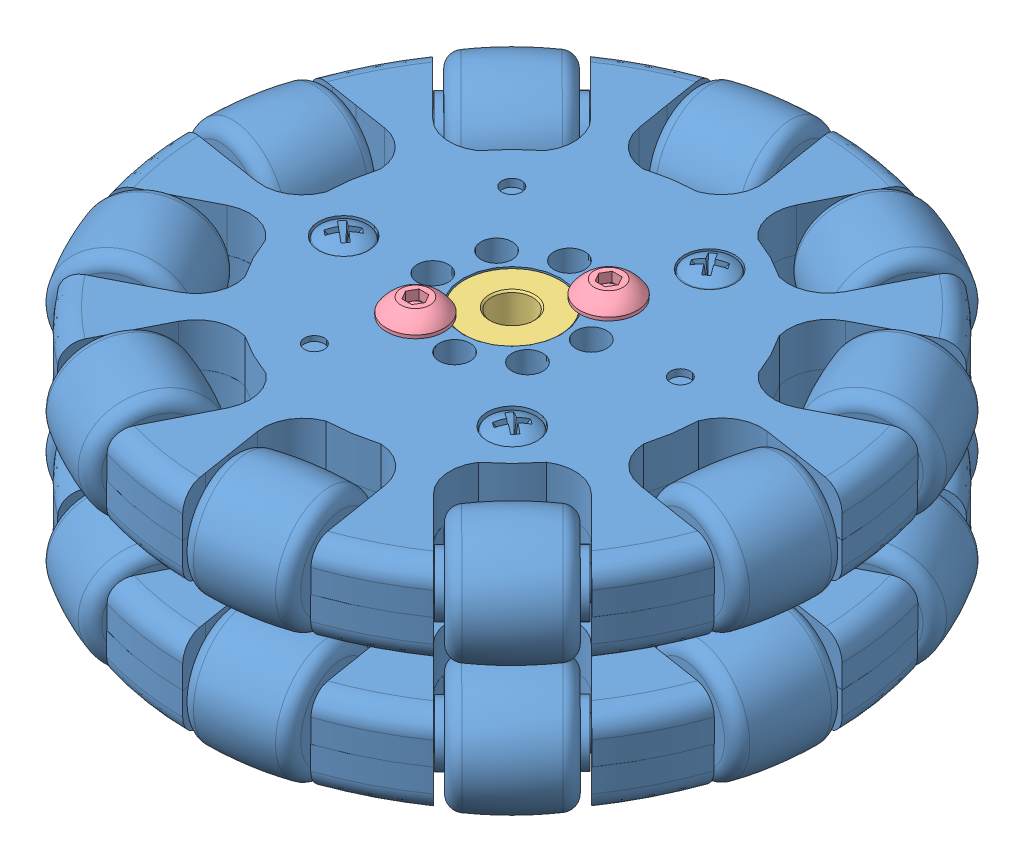
SolidWorks assembly Omni dual wheel spinner, configuration Default. Lengths in mm.
Overall size (77.7 28.71 77.72).
9 component instances, 4 part files, 24 mates.
Components (placement in the parent):
- 3-inch omni single wheel part-1: 3-inch omni single wheel part [Default] at (8.7963 -3.939 -0.2393) size (77.7 13.48 77.72)
- Omni wheel joining hub-1: Omni wheel joining hub [Default] at (1.7244 6.4355 -0.2049) x (0.809625 0 0.586947) z (0 -1 0) size (22 22 5)
- 3-inch omni single wheel part-2: 3-inch omni single wheel part [Default] at (8.7963 11.061 -0.2393) size (77.7 13.48 77.72)
- Axle bronze bushing-1: Axle bronze bushing [Default] at (1.7244 -5.9645 -0.2049) x (0.809625 0 0.586947) z (0 -1 0) size (11 11 12.4)
- Axle bronze bushing-2: Axle bronze bushing [Default] at (1.7244 18.8355 -0.2049) x (-0.809625 0 -0.586947) z (0 1 0) size (11 11 12.4)
- Socket Button Head Cap Screw_AI-2: Socket Button Head Cap Screw_AI [SBHCSCREW 0.138-32x0.5-HX-N] at (-2.9695 20.7897 6.2733) x (0 -1 0) z (0 0 1) size (14.55 6.65 6.65)
- Socket Button Head Cap Screw_AI-3: Socket Button Head Cap Screw_AI [SBHCSCREW 0.138-32x0.5-HX-N] at (6.4183 20.7897 -6.6831) x (0 -1 0) z (0 0 1) size (14.55 6.65 6.65)
- Socket Button Head Cap Screw_AI-4: Socket Button Head Cap Screw_AI [SBHCSCREW 0.138-32x0.5-HX-N] at (-2.9712 -7.9187 6.2721) x (0 1 0) z (0 0 1) size (14.55 6.65 6.65)
- Socket Button Head Cap Screw_AI-5: Socket Button Head Cap Screw_AI [SBHCSCREW 0.138-32x0.5-HX-N] at (6.42 -7.9187 -6.6819) x (0 1 0) z (0 0 1) size (14.55 6.65 6.65)
Mates (geometry in assembly coordinates):
- Concentric1: concentric aligned: circle of 3-inch omni single wheel part-1; cylinder of Axle bronze bushing-1 through (1.7244 6.4355 -0.2049) axis (0 -1 0) radius 3.925
- Concentric3: concentric anti-aligned: cylinder of 3-inch omni single wheel part-1 through (1.7244 -1.0645 -0.2049) axis (0 1 0) radius 4; cylinder of Omni wheel joining hub-1 through (1.7244 8.9355 -0.2049) axis (0 -1 0) radius 4
- Coincident2: coincident anti-aligned: plane of 3-inch omni single wheel part-1 through (-11.9708 3.9355 22.6509) normal (0 1 0); plane of Omni wheel joining hub-1 through (1.7244 3.9355 -0.2049) normal (0 -1 0)
- Coincident11: coincident: point of 3-inch omni single wheel part-1; plane of Omni wheel joining hub-1
- Concentric4: concentric anti-aligned: cylinder of Omni wheel joining hub-1 through (1.7244 8.9355 -0.2049) axis (0 -1 0) radius 4; cylinder of 3-inch omni single wheel part-2 through (1.7244 13.9355 -0.2049) axis (0 1 0) radius 4
- Coincident5: coincident anti-aligned: plane of Omni wheel joining hub-1 through (1.7244 8.9355 -0.2049) normal (0 1 0); plane of 3-inch omni single wheel part-2 through (21.8529 8.9355 17.2533) normal (0 -1 0)
- Coincident12: coincident aligned: plane of 3-inch omni single wheel part-1 through (8.7963 -3.939 -0.2393) normal (0 0 1); plane of 3-inch omni single wheel part-2 through (8.7963 11.061 -0.2393) normal (0 0 1)
- Concentric5: concentric anti-aligned: cylinder of Axle bronze bushing-2 through (1.7244 6.4355 -0.2049) axis (0 1 0) radius 3.925; cylinder of 3-inch omni single wheel part-2 through (1.7244 13.9355 -0.2049) axis (0 -1 0) radius 4
- Concentric7: concentric aligned: cylinder of 3-inch omni single wheel part-2 through (-2.9695 13.9355 6.2733) axis (0 1 0) radius 1.8; cylinder of Socket Button Head Cap Screw_AI-2 through (-2.9695 20.7897 6.2733) axis (0 1 0) radius 3.3274
- Coincident6: coincident anti-aligned: plane of 3-inch omni single wheel part-2 through (-11.9708 18.9355 22.6509) normal (0 1 0); plane of Socket Button Head Cap Screw_AI-2 through (-1.2169 18.9355 6.2733) normal (0 -1 0)
- Concentric8: concentric aligned: cylinder of 3-inch omni single wheel part-2 through (6.4183 13.9355 -6.6831) axis (0 1 0) radius 1.8; cylinder of Socket Button Head Cap Screw_AI-3 through (6.4183 20.7897 -6.6831) axis (0 1 0) radius 3.3274
- Coincident7: coincident anti-aligned: plane of 3-inch omni single wheel part-2 through (-11.9708 18.9355 22.6509) normal (0 1 0); plane of Socket Button Head Cap Screw_AI-3 through (8.1709 18.9355 -6.6831) normal (0 -1 0)
- Concentric9: concentric aligned: cylinder of 3-inch omni single wheel part-1 through (-2.9712 -1.0645 6.2721) axis (0 -1 0) radius 1.8; cylinder of Socket Button Head Cap Screw_AI-4 through (-2.9712 -7.9187 6.2721) axis (0 -1 0) radius 3.3274
- Coincident8: coincident anti-aligned: plane of 3-inch omni single wheel part-1 through (21.8529 -6.0645 17.2533) normal (0 -1 0); plane of Socket Button Head Cap Screw_AI-4 through (-4.7238 -6.0645 6.2721) normal (0 1 0)
- Concentric10: concentric aligned: cylinder of 3-inch omni single wheel part-1 through (6.42 -1.0645 -6.6819) axis (0 -1 0) radius 1.8; cylinder of Socket Button Head Cap Screw_AI-5 through (6.42 -7.9187 -6.6819) axis (0 -1 0) radius 3.3274
- Coincident9: coincident anti-aligned: plane of 3-inch omni single wheel part-1 through (21.8529 -6.0645 17.2533) normal (0 -1 0); plane of Socket Button Head Cap Screw_AI-5 through (4.6674 -6.0645 -6.6819) normal (0 1 0)
- Coincident10: coincident anti-aligned: plane of 3-inch omni single wheel part-1 through (1.7244 -4.5645 -0.2049) normal (0 -1 0); plane of Axle bronze bushing-1 through (1.7244 -4.5645 -0.2049) normal (0 1 0)
- Parallel1: parallel aligned: plane of Omni wheel joining hub-1; plane of Axle bronze bushing-1
- Coincident14: coincident anti-aligned: plane of 3-inch omni single wheel part-2 through (1.7244 17.4355 -0.2049) normal (0 1 0); plane of Axle bronze bushing-2 through (1.7244 17.4355 -0.2049) normal (0 -1 0)
- Parallel2: parallel aligned: plane of Omni wheel joining hub-1; plane of Axle bronze bushing-2
- Parallel3: parallel anti-aligned: plane of assembly; plane of Socket Button Head Cap Screw_AI-5
- Parallel4: parallel anti-aligned: plane of assembly; plane of Socket Button Head Cap Screw_AI-4
- Parallel5: parallel aligned: plane of assembly; plane of Socket Button Head Cap Screw_AI-3
- Parallel6: parallel aligned: plane of assembly; plane of Socket Button Head Cap Screw_AI-2
